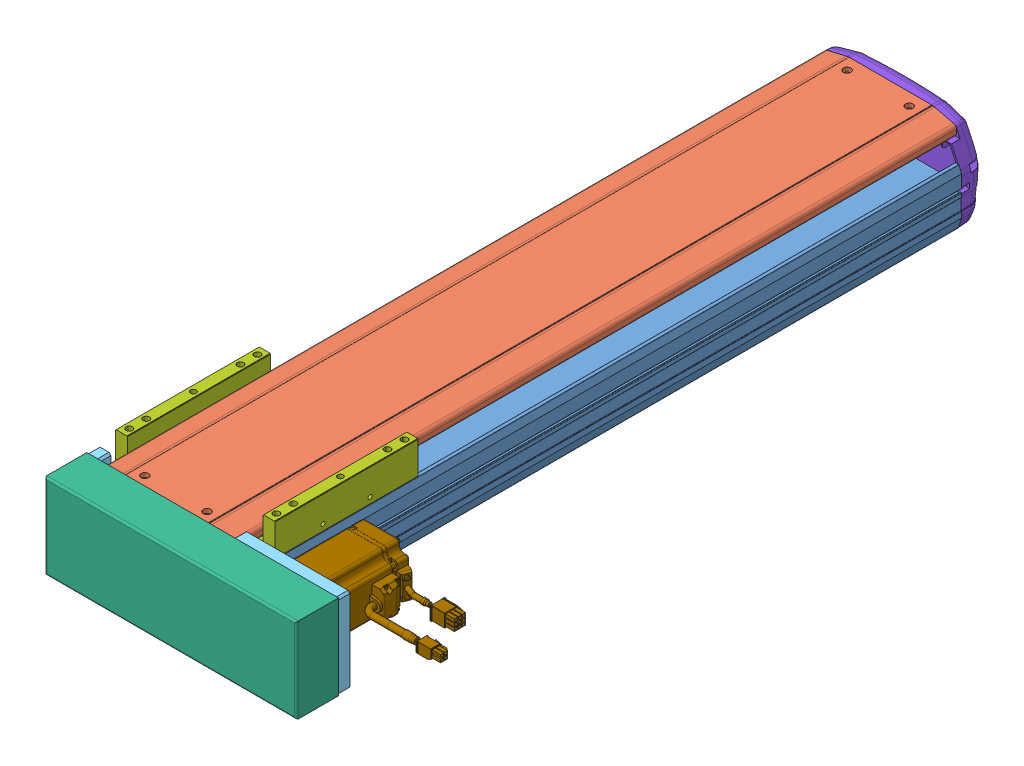
SolidWorks assembly S17-BL-400W, configuration 默认. Lengths in mm.
Overall size (347.7 97.04 833.22).
11 component instances, 9 part files, 38 mates.
Components (placement in the parent):
- S17-BM底座^S17-BL-400W-1: S17-BM底座^S17-BL-400W [默认] at origin size (170 59.5 763.5) (virtual)
- S17-BM上盖^S17-BL-400W-2: S17-BM上盖^S17-BL-400W [默认] at (0 90.5 7.5) size (140 15.5 768) (virtual)
- EE-SX672 传感器^S17-BL-400W-1: EE-SX672 传感器^S17-BL-400W [默认] at (-91.7485 41.1 653.8) x (-1 0 0) z (0 0 1) size (13.5 27.4 26.1) (virtual)
- EE-SX672 传感器^S17-BL-400W-2: EE-SX672 传感器^S17-BL-400W [默认] at (-91.7485 41.1 679.9) x (-1 0 0) z (0 0 1) size (13.5 27.4 26.1) (virtual)
- EE-SX672 传感器^S17-BL-400W-3: EE-SX672 传感器^S17-BL-400W [默认] at (-91.7485 41.1 105.5) x (-1 0 0) z (0 0 1) size (13.5 27.4 26.1) (virtual)
- S17-BL 感应片(外置)^S17-BL-400W-1: S17-BL 感应片(外置)^S17-BL-400W [默认] at (-84.5 76 634) x (-1 0 0) z (0 0 -1) size (8 30 70) (virtual)
- S17-BL-P75电机安装板左转折^S17-BL-400W-1: S17-BL-P75电机安装板左转折^S17-BL-400W [默认] at (-84.4985 1 763.5) size (267 90 12) (virtual)
- S17-BL盖子^S17-BL-400W-1: S17-BL盖子^S17-BL-400W [默认] at (-84.4985 1 775.5) size (267 90 44.5) (virtual)
- S17-BC丝杆螺母连接座^S17-BL-400W-1: S17-BC丝杆螺母连接座^S17-BL-400W [Default] at (0 97 669) size (169 71 152) (virtual)
- 复件 S17塑胶端盖^S17-BL-400W-1: 复件 S17塑胶端盖^S17-BL-400W [Default] at (0 -0.0852 -13) x (-1 0 0) z (0 0 -1) size (170.72 91.84 30.22) (virtual)
- 复件 松下400W电机MHMF042L1U22^S17-BL-400W-1: 复件 松下400W电机MHMF042L1U22^S17-BL-400W [默认] at (130.0015 49.75 763.5) x (0 0 1) z (0 1 0) size (118 149.2 60) (virtual)
Mates (geometry in assembly coordinates):
- 距离10: distance = 97 mm: plane of S17-BC丝杆螺母连接座^S17-BL-400W-1 through (-84 97 745) normal (0 1 0); plane of S17-BM底座^S17-BL-400W-1 through (0 0 763.5) normal (0 -1 0)
- 距离11: distance = 90.5 mm: plane of S17-BM上盖^S17-BL-400W-2 through (-43.7927 90.5 775.5) normal (0 1 0); plane of S17-BM底座^S17-BL-400W-1 through (0 0 763.5) normal (0 -1 0)
- 重合153: coincident: plane of S17-BM底座^S17-BL-400W-1 through (0 0 0) normal (1 0 0); plane of S17-BM上盖^S17-BL-400W-2 through (0 90.5 7.5) normal (1 0 0)
- 重合156: coincident: plane of S17-BM底座^S17-BL-400W-1 through (0 0 0) normal (1 0 0); plane of S17-BC丝杆螺母连接座^S17-BL-400W-1 through (0 97 669) normal (1 0 0)
- 重合157: coincident: plane of EE-SX672 传感器^S17-BL-400W-1 through (-84.9985 52.2 660.1) normal (1 0 0); plane of EE-SX672 传感器^S17-BL-400W-3 through (-84.9985 52.2 111.8) normal (1 0 0)
- 重合158: coincident: plane of EE-SX672 传感器^S17-BL-400W-1 through (-84.9985 52.2 660.1) normal (1 0 0); plane of EE-SX672 传感器^S17-BL-400W-2 through (-84.9985 52.2 686.2) normal (1 0 0)
- 重合159: coincident: plane of EE-SX672 传感器^S17-BL-400W-1 through (-84.9985 52.2 660.1) normal (0 1 0); plane of EE-SX672 传感器^S17-BL-400W-3 through (-84.9985 52.2 111.8) normal (0 1 0)
- 重合160: coincident: plane of EE-SX672 传感器^S17-BL-400W-1 through (-84.9985 52.2 660.1) normal (0 1 0); plane of EE-SX672 传感器^S17-BL-400W-2 through (-84.9985 52.2 686.2) normal (0 1 0)
- 距离20: distance = 30 mm: plane of S17-BM底座^S17-BL-400W-1 through (0 0 763.5) normal (0 -1 0); plane of EE-SX672 传感器^S17-BL-400W-2 through (-84.9985 30 686.2) normal (0 -1 0)
- 同心109: concentric: cylinder of S17-BL 感应片(外置)^S17-BL-400W-1 through (-84.5 69 689.8) axis (1 0 0) radius 2.8; cylinder of S17-BC丝杆螺母连接座^S17-BL-400W-1 through (-84.5 69 694) axis (-1 0 0) radius 2.1
- 同心111: concentric: cylinder of S17-BL 感应片(外置)^S17-BL-400W-1 through (-84.5 69 639.8) axis (1 0 0) radius 2.8; cylinder of S17-BC丝杆螺母连接座^S17-BL-400W-1 through (-84.5 69 644) axis (-1 0 0) radius 2.1
- 重合163: coincident: plane of S17-BC丝杆螺母连接座^S17-BL-400W-1 through (-84.5 62.7074 745) normal (-1 0 0); plane of S17-BL 感应片(外置)^S17-BL-400W-1 through (-84.5 76 634) normal (1 0 0)
- 重合168: coincident: plane of S17-BM底座^S17-BL-400W-1 through (-84.9985 0 763.5) normal (-1 0 0); plane of EE-SX672 传感器^S17-BL-400W-2 through (-84.9985 52.2 686.2) normal (1 0 0)
- 重合169: coincident: plane of EE-SX672 传感器^S17-BL-400W-1 through (-87.9985 33.2 670) normal (0 0 1); plane of EE-SX672 传感器^S17-BL-400W-2 through (-87.9985 33.2 670) normal (0 0 -1)
- 重合170: coincident: plane of S17-BM底座^S17-BL-400W-1 through (0 0 763.5) normal (0 0 1); plane of S17-BL-P75电机安装板左转折^S17-BL-400W-1 through (-84.4985 91 763.5) normal (0 0 -1)
- 重合172: coincident: plane of S17-BM底座^S17-BL-400W-1 through (-84.4985 0 763.5) normal (-1 0 0); plane of S17-BL-P75电机安装板左转折^S17-BL-400W-1 through (-84.4985 1 775.5) normal (-1 0 0)
- 距离23: distance = 1 mm: plane of S17-BL-P75电机安装板左转折^S17-BL-400W-1 through (182.5015 1 775.5) normal (0 -1 0); plane of S17-BM底座^S17-BL-400W-1 through (0 0 763.5) normal (0 -1 0)
- 重合176: coincident: plane of S17-BL-P75电机安装板左转折^S17-BL-400W-1 through (-84.4985 91 775.5) normal (0 0 1); plane of S17-BL盖子^S17-BL-400W-1 through (49.0015 46 775.5) normal (0 0 -1)
- 重合177: coincident: plane of S17-BL-P75电机安装板左转折^S17-BL-400W-1 through (182.5015 91 775.5) normal (1 0 0); plane of S17-BL盖子^S17-BL-400W-1 through (182.5015 24.2 820.3) normal (1 0 0)
- 重合178: coincident: plane of S17-BL-P75电机安装板左转折^S17-BL-400W-1 through (182.5015 1 775.5) normal (0 -1 0); plane of S17-BL盖子^S17-BL-400W-1 through (182.5015 1 775.5) normal (0 -1 0)
- 重合180: coincident: plane of S17-BM底座^S17-BL-400W-1 through (0 0 0) normal (0 0 1); plane of assembly through (0 0 0) normal (0 0 1)
- 重合181: coincident: plane of S17-BM底座^S17-BL-400W-1 through (0 0 0) normal (0 1 0); plane of assembly through (0 0 0) normal (0 1 0)
- 重合182: coincident: plane of S17-BM底座^S17-BL-400W-1 through (0 0 0) normal (1 0 0); plane of assembly through (0 0 0) normal (1 0 0)
- 重合187: coincident: plane of S17-BM上盖^S17-BL-400W-2 through (68.2998 76.7 775.5) normal (0 0 1); plane of S17-BL盖子^S17-BL-400W-1 through (49.0015 46 775.5) normal (0 0 -1)
- 重合188: coincident: plane of S17-BM底座^S17-BL-400W-1 through (96.5232 59.4999 17) normal (0 0 -1); plane of 复件 S17塑胶端盖^S17-BL-400W-1 through (0 -0.0852 17) normal (0 0 1)
- 重合189: coincident: line of S17-BM上盖^S17-BL-400W-2 through (43.7927 90.5 7.5) axis (-1 0 0); line of 复件 S17塑胶端盖^S17-BL-400W-1 through (43.4408 90.5 7.5) axis (-1 0 0)
- 重合190: coincident: line of S17-BM底座^S17-BL-400W-1 through (79.4985 35.3956 17) axis (0 1 0); line of 复件 S17塑胶端盖^S17-BL-400W-1 through (79.4985 38.7648 17) axis (0 -1 0)
- 距离25: distance = 22.5 mm: plane of 复件 松下400W电机MHMF042L1U22^S17-BL-400W-1 through (160.0015 24.75 692) normal (1 0 0); plane of S17-BL-P75电机安装板左转折^S17-BL-400W-1 through (182.5015 91 775.5) normal (1 0 0)
- 距离26: distance = 138 mm: plane of S17-BL盖子^S17-BL-400W-1 through (49.0015 46 820) normal (0 0 1); plane of EE-SX672 传感器^S17-BL-400W-2 through (-98.4985 30 686.2) normal (0 0 1)
- 距离27: distance = 88.5 mm: plane of EE-SX672 传感器^S17-BL-400W-3 through (-98.4985 30 105.5) normal (0 0 -1); plane of 复件 S17塑胶端盖^S17-BL-400W-1 through (0 -0.0852 17) normal (0 0 1)
- 宽度4: width: plane of S17-BL 感应片(外置)^S17-BL-400W-1 through (-85.3 63 658.3) normal (0 0 -1); plane of S17-BL 感应片(外置)^S17-BL-400W-1 through (-85.3 46 673.3) normal (0 0 1); plane of EE-SX672 传感器^S17-BL-400W-1 through (-98.4985 30 655.9) normal (0 0 1); plane of EE-SX672 传感器^S17-BL-400W-2 through (-98.4985 30 675.7) normal (0 0 -1)
- 重合194: coincident: plane of S17-BL-P75电机安装板左转折^S17-BL-400W-1 through (-84.4985 1 761) normal (0 0 -1); plane of 复件 松下400W电机MHMF042L1U22^S17-BL-400W-1 through (155.0015 71 761) normal (0 0 1)
- 距离28: distance = 18.75 mm: plane of 复件 松下400W电机MHMF042L1U22^S17-BL-400W-1 through (105.0015 19.75 692) normal (0 -1 0); plane of S17-BL-P75电机安装板左转折^S17-BL-400W-1 through (182.5015 1 775.5) normal (0 -1 0)
- 重合195: coincident: plane of S17-BL-P75电机安装板左转折^S17-BL-400W-1 through (-84.4985 91 763.5) normal (0 0 -1); plane of 复件 松下400W电机MHMF042L1U22^S17-BL-400W-1 through (155.0015 74.75 763.5) normal (0 0 1)
- 距离29: distance = 151 mm: plane of S17-BL盖子^S17-BL-400W-1 through (49.0015 46 820) normal (0 0 1); cylinder of S17-BC丝杆螺母连接座^S17-BL-400W-1 through (78 97 669) axis (0 1 0) radius 3
- 同心112: concentric: cylinder of S17-BL 感应片(外置)^S17-BL-400W-1 through (-84.5 69 694) axis (1 0 0) radius 2.8; cylinder of S17-BC丝杆螺母连接座^S17-BL-400W-1 through (-84.5 69 694) axis (-1 0 0) radius 2.1
- 同心113: concentric: cylinder of S17-BL 感应片(外置)^S17-BL-400W-1 through (-84.5 69 644) axis (1 0 0) radius 2.8; cylinder of S17-BC丝杆螺母连接座^S17-BL-400W-1 through (-84.5 69 644) axis (-1 0 0) radius 2.1
- 宽度5: width: plane of EE-SX672 传感器^S17-BL-400W-1 through (-98.4985 30 660.1) normal (0 0 1); plane of EE-SX672 传感器^S17-BL-400W-2 through (-98.4985 30 679.9) normal (0 0 -1); plane of S17-BL 感应片(外置)^S17-BL-400W-1 through (-85.3 46 677.5) normal (0 0 1); plane of S17-BL 感应片(外置)^S17-BL-400W-1 through (-85.3 63 662.5) normal (0 0 -1)
